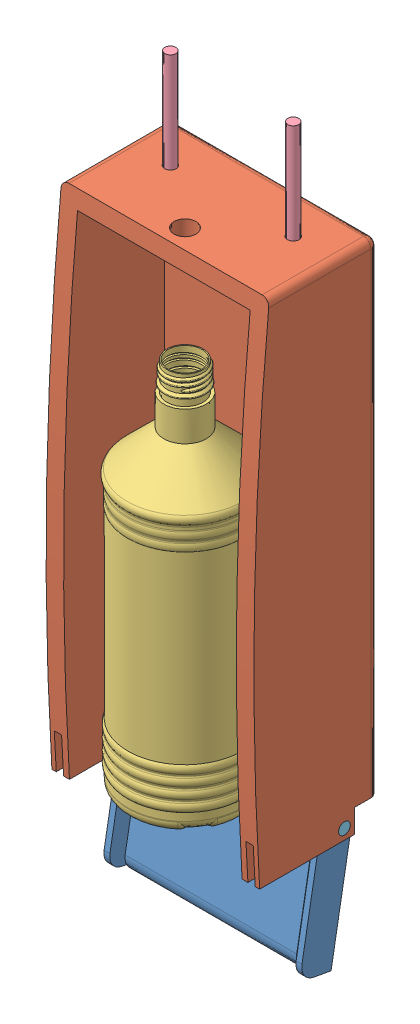
SolidWorks assembly chamber assembled, configuration Default. Lengths in mm.
Overall size (150 490.3 117.8).
6 component instances, 5 part files, 10 mates.
Components (placement in the parent):
- Base_forBottle-1: Base_forBottle [Default] at (28.6189 35.0665 -48.0778) x (-1 0 0) z (0 -0.984808 0.173648) size (135.25 22 90)
- chamber-1: chamber [Default] at (28.8439 53.2318 -29.4789) x (-1 0 0) z (0 0 -1) size (142 346 84.97)
- Battery Water Bottle HDPE-1: Battery Water Bottle HDPE [Default] at (28.8439 78.9318 -29.4789) x (-0.812388 0 -0.583118) z (0.583118 0 -0.812388) size (81.4 253.7 81.4)
- rotation_guide-2: rotation_guide [Default] at (-13.1561 387.2318 -61.4789) x (0.14568 0 -0.989332) z (0 1 0) size (7.5 7.5 90)
- rotation_guide-3: rotation_guide [Default] at (70.8439 477.2318 -61.4789) x (0.999126 0 -0.041803) z (0 -1 0) size (7.5 7.5 90)
- arbre servo-1: arbre servo [Default] at (-50.1561 70.2318 -67.4789) x (0 0 -1) z (1 0 0) size (8 8 150)
Mates (geometry in assembly coordinates):
- Concentric1: concentric anti-aligned: circle of Base_forBottle-1; circle of chamber-1
- Distance2: distance = 0.15 mm anti-aligned: plane of Base_forBottle-1 through (-39.0061 75.5626 -77.5577) normal (-1 0 0); plane of chamber-1 through (-39.1561 88.2318 -76.2366) normal (1 0 0)
- LimitAngle2: limit planar angle = 1.396263 rad anti-aligned: plane of Base_forBottle-1 through (-35.0061 76.0835 -74.6033) normal (0 0.173648 0.984808); plane of chamber-1 through (28.8439 63.2318 -29.4789) normal (0 -1 0)
- Concentric5: concentric aligned: circle of chamber-1; circle of Battery Water Bottle HDPE-1
- Concentric6: concentric aligned: circle of chamber-1; circle of rotation_guide-2
- Concentric7: concentric anti-aligned: circle of chamber-1; circle of rotation_guide-3
- LimitDistance4: limit distance = 10 mm aligned: plane of rotation_guide-2 through (-13.1561 387.2318 -61.4789) normal (0 -1 0); plane of chamber-1 through (28.8439 397.2318 15.5211) normal (0 -1 0)
- LimitDistance3: limit distance = 10 mm aligned: plane of rotation_guide-3 through (70.8439 387.2318 -61.4789) normal (0 -1 0); plane of chamber-1 through (100.5439 397.2318 15.5211) normal (0 -1 0)
- Concentric8: concentric anti-aligned: circle of chamber-1; circle of arbre servo-1
- Coincident7: coincident aligned: plane of chamber-1 through (99.8439 63.2318 15.5211) normal (1 0 0); plane of arbre servo-1 through (99.8439 70.2318 -67.4789) normal (1 0 0)
